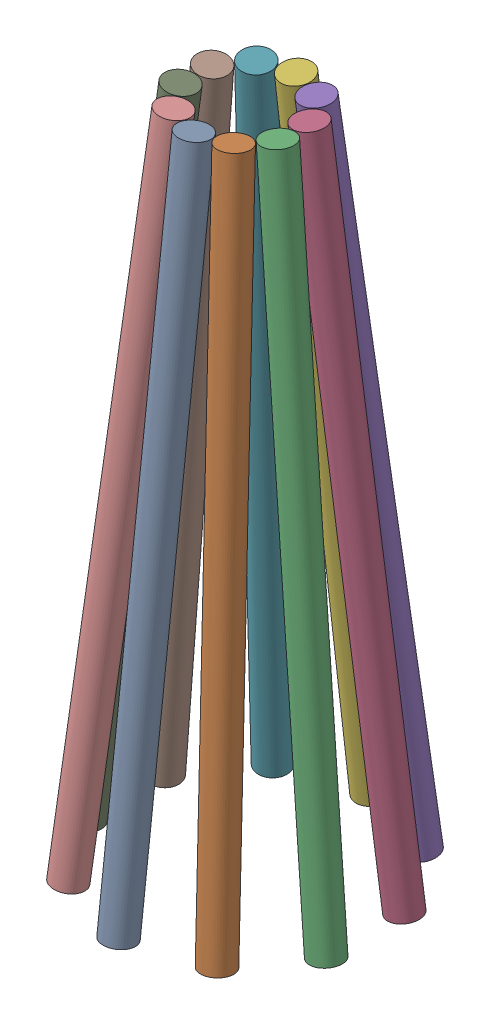
SolidWorks assembly ALLIANCE_STATION_GP3_ASM, configuration Default. Lengths in mm.
Overall size (575.4 1369.97 584.38).
10 component instances, 1 part files, 0 mates.
Components (placement in the parent):
- LITTER-1: LITTER [Default] at (0 44.0649 183.0112) x (1 0 0) z (0 0.113203 0.993572) size (63.5 1371.6 63.5)
- LITTER-2: LITTER [Default] at (107.5713 44.0649 148.0592) x (0.809017 0 -0.587785) z (0.584007 0.113203 0.803817) size (63.5 1371.6 63.5)
- LITTER-3: LITTER [Default] at (174.054 44.0649 56.5536) x (0.309017 0 -0.951057) z (0.944943 0.113203 0.307031) size (63.5 1371.6 63.5)
- LITTER-4: LITTER [Default] at (174.054 44.0649 -56.5536) x (-0.309017 0 -0.951057) z (0.944943 0.113203 -0.307031) size (63.5 1371.6 63.5)
- LITTER-5: LITTER [Default] at (107.5713 44.0649 -148.0592) x (-0.809017 0 -0.587785) z (0.584007 0.113203 -0.803817) size (63.5 1371.6 63.5)
- LITTER-6: LITTER [Default] at (0 44.0649 -183.0112) x (-1 0 0) z (0 0.113203 -0.993572) size (63.5 1371.6 63.5)
- LITTER-7: LITTER [Default] at (-107.5713 44.0649 -148.0592) x (-0.809017 0 0.587785) z (-0.584007 0.113203 -0.803817) size (63.5 1371.6 63.5)
- LITTER-8: LITTER [Default] at (-174.054 44.0649 -56.5536) x (-0.309017 0 0.951057) z (-0.944943 0.113203 -0.307031) size (63.5 1371.6 63.5)
- LITTER-9: LITTER [Default] at (-174.054 44.0649 56.5536) x (0.309017 0 0.951057) z (-0.944943 0.113203 0.307031) size (63.5 1371.6 63.5)
- LITTER-10: LITTER [Default] at (-107.5713 44.0649 148.0592) x (0.809017 0 0.587785) z (-0.584007 0.113203 0.803817) size (63.5 1371.6 63.5)
